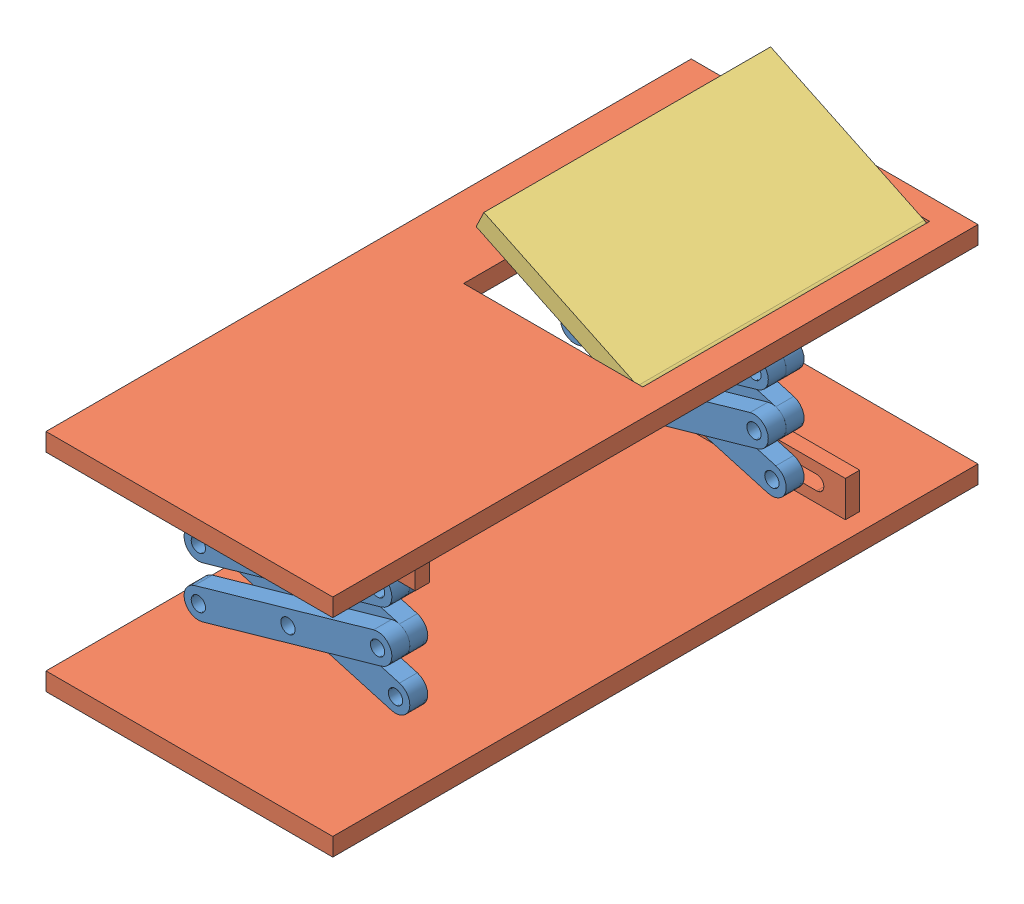
SolidWorks assembly ladder assemb with table, configuration Default. Lengths in mm.
Overall size (86.68 92.45 180).
17 component instances, 3 part files, 15 mates.
Components (placement in the parent):
- ladder assemb-1: ladder assemb [Default] at (-59.0134 24.7734 48.0583) x (-0.27467 0.961538 0) z (0.961538 0.27467 0) size (66.64 10 68.06) (flexible)
  - link-1: link [Default] at (-11.1875 -10.5583 11.3781) size (8 5 60)
  - link-2: link [Default] at (-11.1875 -15.5583 11.3781) x (-0.849112 0 -0.528212) z (0.528212 0 -0.849112) size (8 5 60)
  - link-3: link [Default] at (2.546 -10.5583 15.3012) size (8 5 60)
  - link-4: link [Default] at (2.546 -15.5583 15.3012) x (-0.849112 0 -0.528212) z (0.528212 0 -0.849112) size (8 5 60)
  - link-5: link [Default] at (16.2796 -10.5583 19.2243) size (8 5 60)
  - link-6: link [Default] at (16.2796 -15.5583 19.2243) x (-0.849112 0 -0.528212) z (0.528212 0 -0.849112) size (8 5 60)
- ladder assemb-2: ladder assemb [Default] at (-59.0134 24.7734 153.0583) x (-0.27467 0.961538 0) z (0.961538 0.27467 0) size (66.64 10 68.06) (flexible)
  - link-1: link [Default] at (-11.1875 -10.5583 11.3781) size (8 5 60)
  - link-2: link [Default] at (-11.1875 -15.5583 11.3781) x (-0.849112 0 -0.528212) z (0.528212 0 -0.849112) size (8 5 60)
  - link-3: link [Default] at (2.546 -10.5583 15.3012) size (8 5 60)
  - link-4: link [Default] at (2.546 -15.5583 15.3012) x (-0.849112 0 -0.528212) z (0.528212 0 -0.849112) size (8 5 60)
  - link-5: link [Default] at (16.2796 -10.5583 19.2243) size (8 5 60)
  - link-6: link [Default] at (16.2796 -15.5583 19.2243) x (-0.849112 0 -0.528212) z (0.528212 0 -0.849112) size (8 5 60)
- table-1: table [writing side] at (-40 57.8486 90) x (0 0 -1) z (1 0 0) size (180 15 80)
- table-2: table [Default] at (-40 5 90) x (0 0 1) z (1 0 0) size (180 15 80)
- writing pad-1: writing pad [Default] at (-38.2 70.7989 90) x (0 0 -1) z (0.430729 0.902481 0) size (86 50 5)
Mates (geometry in assembly coordinates):
- Concentric1: concentric aligned: cylinder of ladder assemb-1/link-1 through (-70 10 42.5) axis (0 0 -1) radius 2; cylinder of ladder assemb-2/link-1 through (-70 10 147.5) axis (0 0 -1) radius 2
- Distance1: distance = 100 mm anti-aligned: plane of ladder assemb-1/link-1 through (-20 24.2829 42.5) normal (0 0 1); plane of ladder assemb-2/link-1 through (-20 24.2829 142.5) normal (0 0 -1)
- Concentric2: concentric aligned: cylinder of ladder assemb-1/link-2 through (-20 10 37.5) axis (0 0 -1) radius 2; cylinder of ladder assemb-2/link-2 through (-20 10 142.5) axis (0 0 -1) radius 2
- Width1: width aligned: plane of table-1 through (0 62.8486 180) normal (0 0 1); plane of table-1 through (0 62.8486 0) normal (0 0 -1); plane of ladder assemb-2/link-5 through (-20 52.8486 147.5) normal (0 0 1); plane of ladder assemb-1/link-6 through (-70 52.8486 32.5) normal (0 0 -1)
- Concentric3: concentric anti-aligned: cylinder of ladder assemb-2/link-6 through (-70 52.8486 142.5) axis (0 0 -1) radius 2; cylinder of table-1 through (-70 52.8486 138) axis (0 0 1) radius 2
- Tangent1: tangent anti-aligned: cylinder of ladder assemb-2/link-5 through (-20 52.8486 147.5) axis (0 0 -1) radius 2; plane of table-1 through (-64 54.8486 180) normal (0 -1 0)
- Parallel1: parallel aligned: plane of table-1 through (-40 62.8486 90) normal (0 1 0); plane of table-2 through (-40 5 90) normal (0 1 0)
- Coincident3: coincident anti-aligned: plane of table-2 through (0 0 0) normal (0 0 -1); plane of assembly through (0 0 0) normal (0 0 1)
- Coincident4: coincident aligned: plane of table-2 through (0 0 180) normal (1 0 0); plane of assembly through (0 0 0) normal (1 0 0)
- Coincident5: coincident anti-aligned: plane of table-2 through (-40 0 90) normal (0 -1 0); plane of assembly through (0 0 0) normal (0 1 0)
- Concentric5: concentric aligned: cylinder of ladder assemb-1/link-1 through (-70 10 42.5) axis (0 0 -1) radius 2; cylinder of table-2 through (-70 10 42) axis (0 0 -1) radius 2
- Coincident6: coincident aligned: plane of table-1 through (0 62.8486 0) normal (0 0 -1); plane of table-2 through (0 0 0) normal (0 0 -1)
- Concentric6: concentric anti-aligned: cylinder of table-1 through (-10.5 60.3486 96.2426) axis (0 0 -1) radius 1.5; cylinder of writing pad-1 through (-10.5 60.3486 -4.2426) axis (0 0 1) radius 1.5
- Coincident10: coincident anti-aligned: plane of table-1 through (-57.5 47.8486 89) normal (0 0 -1); plane of writing pad-1 through (-10.5 60.3486 89) normal (0 0 1)
- Distance3: distance = 50 mm: axis of ladder assemb-1/link-2 through (-20 10 37.5) axis (0 0 -1); axis of table-2 through (-70 10 42) axis (0 0 -1)
